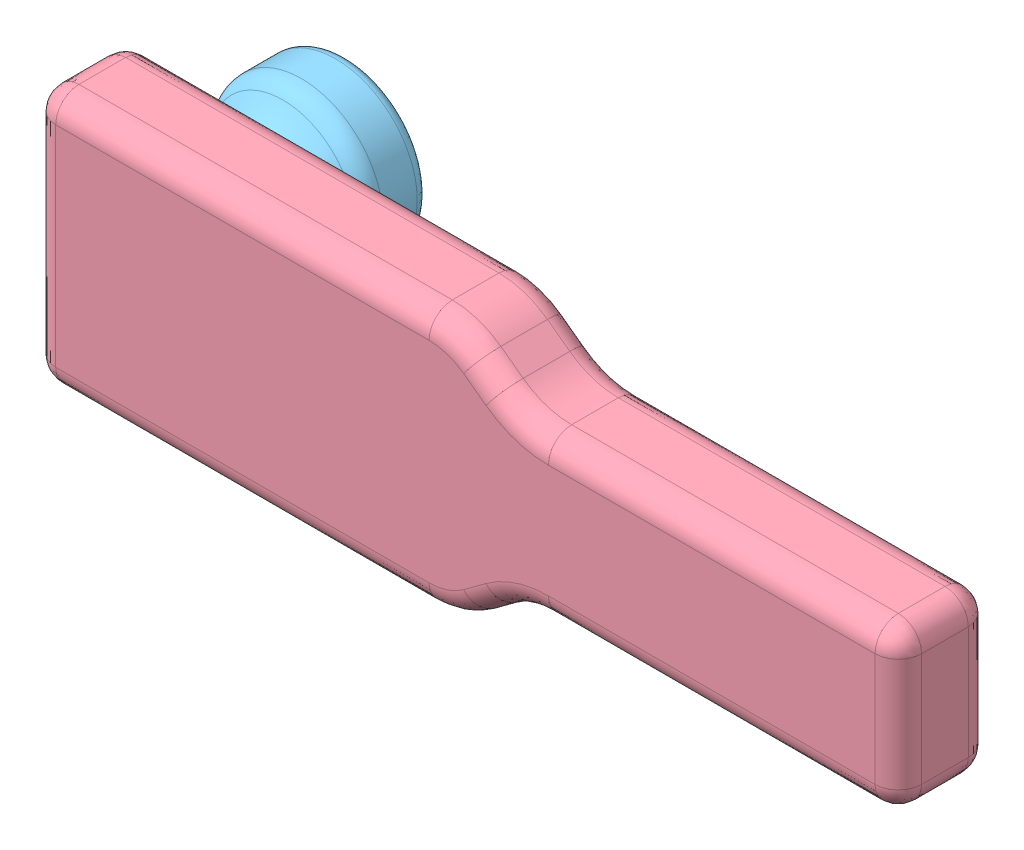
SolidWorks assembly OverAllModel, configuration Default. Lengths in mm.
Overall size (74.24 22 20).
5 component instances, 5 part files, 10 mates.
Components (placement in the parent):
- IMU-1: IMU [Default] at (-40.4381 1.2509 6.4903) size (34.29 10.16 3)
- ArduinoProMini-1: ArduinoProMini [Default] at (-75.4581 15.2209 6.4903) x (0 -1 0) z (0 0 1) size (17.78 33.02 3)
- PCB-1: PCB [Default] at (-36.4381 -2.5591 4.4903) x (0 1 0) z (0 0 1) size (17.78 39.02 2)
- CaseModel-1: CaseModel [Default] at (-75.9178 -2.6691 10.9903) x (-1 0 0) z (0 0 -1) size (74.23 22 8)
- EarPlug-1: EarPlug [Default] at (-70.9284 6.2228 2.9903) x (0 0 1) z (-1 0 0) size (12 14 14)
Mates (geometry in assembly coordinates):
- Distance2: distance = 2 mm anti-aligned: plane of ArduinoProMini-1 through (-42.4381 15.2209 9.4903) normal (1 0 0); plane of IMU-1 through (-40.4381 11.4109 9.4903) normal (-1 0 0)
- Coincident2: coincident aligned: plane of IMU-1 through (-40.4381 1.2509 9.4903) normal (0 0 1); plane of ArduinoProMini-1 through (-75.4581 15.2209 9.4903) normal (0 0 1)
- Width1: width aligned: plane of ArduinoProMini-1 through (-42.4381 15.2209 9.4903) normal (0 1 0); plane of ArduinoProMini-1 through (-42.4381 -2.5591 9.4903) normal (0 -1 0); plane of IMU-1 through (-40.4381 11.4109 9.4903) normal (0 1 0); plane of IMU-1 through (-40.4381 1.2509 9.4903) normal (0 -1 0)
- Distance3: distance = 0 mm aligned: plane of ArduinoProMini-1 through (-75.4581 15.2209 9.4903) normal (-1 0 0); plane of PCB-1 through (-75.4581 -2.5591 6.4903) normal (-1 0 0)
- Width2: width aligned: plane of PCB-1 through (-75.4581 15.2209 6.4903) normal (0 1 0); plane of PCB-1 through (-75.4581 -2.5591 6.4903) normal (0 -1 0); plane of ArduinoProMini-1 through (-42.4381 15.2209 9.4903) normal (0 1 0); plane of ArduinoProMini-1 through (-42.4381 -2.5591 9.4903) normal (0 -1 0)
- Coincident4: coincident anti-aligned: plane of ArduinoProMini-1 through (-75.4581 15.2209 6.4903) normal (0 0 -1); plane of PCB-1 through (-36.4381 -2.5591 6.4903) normal (0 0 1)
- Width3: width aligned: plane of CaseModel-1 through (-43.9178 2.3309 10.9903) normal (0 0 1); plane of CaseModel-1 through (-43.9178 2.3309 2.9903) normal (0 0 -1); plane of ArduinoProMini-1 through (-75.4581 15.2209 9.4903) normal (0 0 1); plane of PCB-1 through (-36.4381 -2.5591 4.4903) normal (0 0 -1)
- Width4: width anti-aligned: plane of CaseModel-1 through (-77.9178 -2.6691 2.9903) normal (-1 0 0); plane of CaseModel-1 through (-3.6885 11.1809 2.9903) normal (1 0 0); plane of IMU-1 through (-6.1481 11.4109 9.4903) normal (1 0 0); plane of PCB-1 through (-75.4581 -2.5591 6.4903) normal (-1 0 0)
- Width5: width anti-aligned: plane of CaseModel-1 through (-75.9178 17.3309 2.9903) normal (0 1 0); plane of CaseModel-1 through (-43.9178 -4.6691 2.9903) normal (0 -1 0); plane of PCB-1 through (-75.4581 -2.5591 6.4903) normal (0 -1 0); plane of PCB-1 through (-75.4581 15.2209 6.4903) normal (0 1 0)
- Coincident5: coincident anti-aligned: plane of CaseModel-1 through (-43.9178 2.3309 2.9903) normal (0 0 -1); plane of EarPlug-1 through (-70.9284 9.7228 2.9903) normal (0 0 1)
